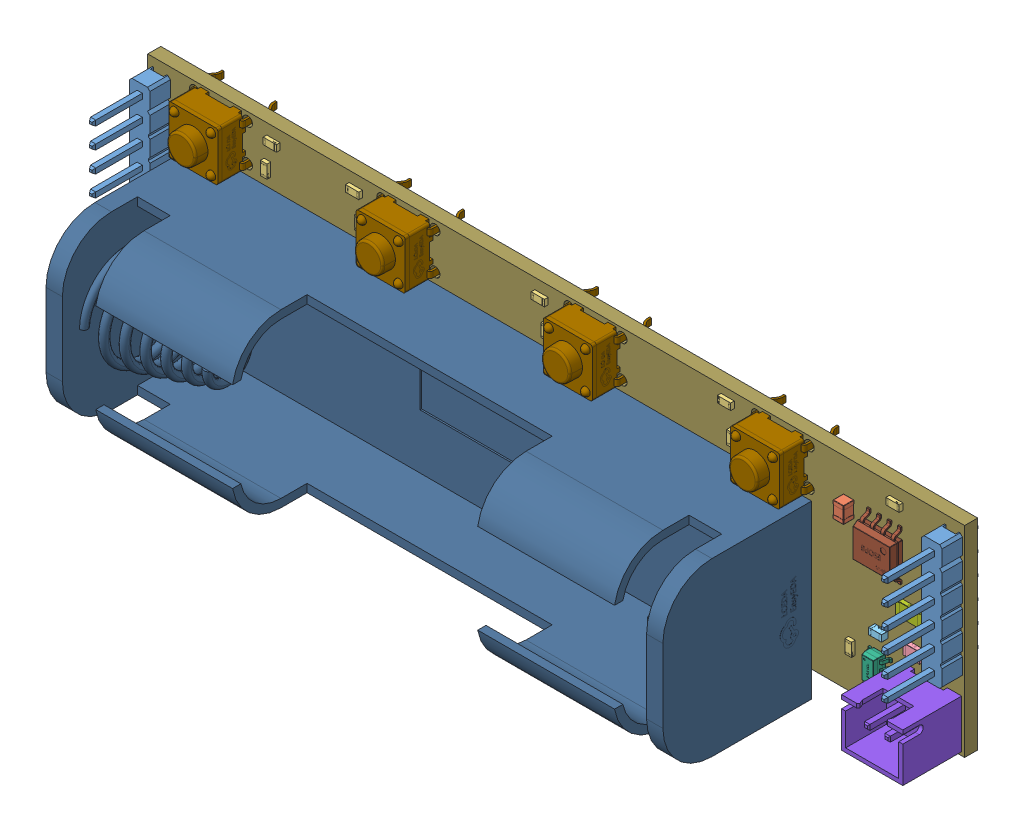
SolidWorks assembly 3D_PCB_PCB_18650_POWER_CHARGE_2024-03-23_2024-03-23, configuration 默认. Lengths in mm.
Overall size (99.98 27.76 23.2).
77 component instances, 12 part files, 0 mates.
Components (placement in the parent):
- 3D_PCB_PCB_18650_POWER_CHARGE_2024-03-23_2024-03-23.step-1: 3D_PCB_PCB_18650_POWER_CHARGE_2024-03-23_2024-03-23.step [默认] at origin size (99.98 27.76 23.2)
  - H1.step-1: H1.step [默认] at (2.8372 42.3622 1.6) x (0 1 0) z (0 0 1) size (15.25 2.5 11.5)
    - footprint_f8ae.step-1: footprint_f8ae.step [默认] at origin size (15.25 2.5 11.5)
      - SOLID.step-1: SOLID.step [默认] at origin size (15.25 2.5 11.5)
  - H2.step-1: H2.step [默认] at (99.7866 42.3546 1.6) x (0 1 0) z (0 0 1) size (15.25 2.5 11.5)
    - footprint_f8ae.step-1: footprint_f8ae.step [默认] at origin size (15.25 2.5 11.5)
      - SOLID.step-1: SOLID.step [默认] at origin size (15.25 2.5 11.5)
  - C1.step-1: C1.step [默认] at (87.1222 45.9919 1.6) x (0 1 0) z (0 0 1) size (2 1.3 1.3)
    - footprint_bf19.step-1: footprint_bf19.step [默认] at origin size (2 1.3 1.3)
      - SOLID-0.step-1: SOLID-0.step [默认] at origin size (2 1.3 1.3)
  - R2.step-1: R2.step [默认] at (16.7082 49.3294 1.6) x (-1 0 0) z (0 0 1) size (1.62 0.81 0.45)
    - footprint_4858.step-1: footprint_4858.step [默认] at origin size (1.62 0.81 0.45)
      - COMPOUND.step-1: COMPOUND.step [默认] at origin size (1.62 0.81 0.45)
  - R7.step-1: R7.step [默认] at (49.5098 49.3294 1.6) size (1.62 0.81 0.45)
    - footprint_4858.step-1: footprint_4858.step [默认] at origin size (1.62 0.81 0.45)
      - COMPOUND.step-1: COMPOUND.step [默认] at origin size (1.62 0.81 0.45)
  - R6.step-1: R6.step [默认] at (73.0251 46.2891 1.6) x (0 1 0) z (0 0 1) size (1.62 0.81 0.45)
    - footprint_4858.step-1: footprint_4858.step [默认] at origin size (1.62 0.81 0.45)
      - COMPOUND.step-1: COMPOUND.step [默认] at origin size (1.62 0.81 0.45)
  - R8.step-1: R8.step [默认] at (50.3226 46.2891 1.6) x (0 1 0) z (0 0 1) size (1.62 0.81 0.45)
    - footprint_4858.step-1: footprint_4858.step [默认] at origin size (1.62 0.81 0.45)
      - COMPOUND.step-1: COMPOUND.step [默认] at origin size (1.62 0.81 0.45)
  - R9.step-1: R9.step [默认] at (27.5083 46.2891 1.6) x (0 1 0) z (0 0 1) size (1.62 0.81 0.45)
    - footprint_4858.step-1: footprint_4858.step [默认] at origin size (1.62 0.81 0.45)
      - COMPOUND.step-1: COMPOUND.step [默认] at origin size (1.62 0.81 0.45)
  - R10.step-1: R10.step [默认] at (15.969 46.2891 1.6) x (0 1 0) z (0 0 1) size (1.62 0.81 0.45)
    - footprint_4858.step-1: footprint_4858.step [默认] at origin size (1.62 0.81 0.45)
      - COMPOUND.step-1: COMPOUND.step [默认] at origin size (1.62 0.81 0.45)
  - R3.step-1: R3.step [默认] at (92.9286 49.2583 1.6) x (-1 0 0) z (0 0 1) size (1.62 0.81 0.45)
    - footprint_4858.step-1: footprint_4858.step [默认] at origin size (1.62 0.81 0.45)
      - COMPOUND.step-1: COMPOUND.step [默认] at origin size (1.62 0.81 0.45)
  - R5.step-1: R5.step [默认] at (72.2962 49.7358 1.6) size (1.62 0.81 0.45)
    - footprint_4858.step-1: footprint_4858.step [默认] at origin size (1.62 0.81 0.45)
      - COMPOUND.step-1: COMPOUND.step [默认] at origin size (1.62 0.81 0.45)
  - R26.step-1: R26.step [默认] at (87.5032 31.3691 1.6) x (0 1 0) z (0 0 1) size (1.62 0.81 0.45)
    - footprint_4858.step-1: footprint_4858.step [默认] at origin size (1.62 0.81 0.45)
      - COMPOUND.step-1: COMPOUND.step [默认] at origin size (1.62 0.81 0.45)
  - R1.step-1: R1.step [默认] at (26.7894 49.3294 1.6) size (1.62 0.81 0.45)
    - footprint_4858.step-1: footprint_4858.step [默认] at origin size (1.62 0.81 0.45)
      - COMPOUND.step-1: COMPOUND.step [默认] at origin size (1.62 0.81 0.45)
  - R25.step-1: R25.step [默认] at (95.3772 34.7981 1.6) size (2 1.3 0.61)
    - footprint_7ba0.step-1: footprint_7ba0.step [默认] at origin size (2 1.3 0.61)
      - COMPOUND-1.step-1: COMPOUND-1.step [默认] at origin size (2 1.3 0.61)
  - C37.step-1: C37.step [默认] at (91.1227 34.76 1.6) size (1.6 0.8 0.8)
    - footprint_33f1.step-1: footprint_33f1.step [默认] at origin size (1.6 0.8 0.8)
      - SOLID-2.step-1: SOLID-2.step [默认] at origin size (1.6 0.8 0.8)
  - C36.step-1: C36.step [默认] at (90.4496 28.7021 1.6) x (-1 0 0) z (0 0 1) size (1.6 0.8 0.8)
    - footprint_33f1.step-1: footprint_33f1.step [默认] at origin size (1.6 0.8 0.8)
      - SOLID-2.step-1: SOLID-2.step [默认] at origin size (1.6 0.8 0.8)
  - U12.step-1: U12.step [默认] at (91.0592 31.3691 1.6) x (-1 0 0) z (0 0 1) size (2.81 2.9 1.65)
    - footprint_4915.step-1: footprint_4915.step [默认] at origin size (2.81 2.9 1.65)
      - COMPOUND-3.step-1: COMPOUND-3.step [默认] at origin size (2.81 2.9 1.65)
  - R4.step-1: R4.step [默认] at (94.9962 38.6817 1.6) size (3.2 1.6 0.56)
    - footprint_4e6b.step-1: footprint_4e6b.step [默认] at origin size (3.2 1.6 0.56)
      - COMPOUND-4.step-1: COMPOUND-4.step [默认] at origin size (3.2 1.6 0.56)
  - CN2.step-1: CN2.step [默认] at (97.2822 30.4801 1.6) size (7.5 5.9 10.6)
    - footprint_8315.step-1: footprint_8315.step [默认] at origin size (7.5 5.9 10.6)
      - COMPOUND-5.step-1: COMPOUND-5.step [默认] at origin size (7.5 5.9 10.6)
  - SW3.step-1: SW3.step [默认] at (56.1265 47.7496 1.6) x (-1 0 0) z (0 0 1) size (8.21 6 8.4)
    - footprint_ad6a.step-1: footprint_ad6a.step [默认] at origin size (8.21 6 8.4)
      - COMPOUND-6.step-1: COMPOUND-6.step [默认] at origin size (8.21 6 8.4)
  - SW2.step-1: SW2.step [默认] at (33.2334 47.7496 1.6) x (-1 0 0) z (0 0 1) size (8.21 6 8.4)
    - footprint_ad6a.step-1: footprint_ad6a.step [默认] at origin size (8.21 6 8.4)
      - COMPOUND-6.step-1: COMPOUND-6.step [默认] at origin size (8.21 6 8.4)
  - SW4.step-1: SW4.step [默认] at (79.045 47.7496 1.6) x (-1 0 0) z (0 0 1) size (8.21 6 8.4)
    - footprint_ad6a.step-1: footprint_ad6a.step [默认] at origin size (8.21 6 8.4)
      - COMPOUND-6.step-1: COMPOUND-6.step [默认] at origin size (8.21 6 8.4)
  - SW1.step-1: SW1.step [默认] at (10.2921 47.7496 1.6) x (-1 0 0) z (0 0 1) size (8.21 6 8.4)
    - footprint_ad6a.step-1: footprint_ad6a.step [默认] at origin size (8.21 6 8.4)
      - COMPOUND-6.step-1: COMPOUND-6.step [默认] at origin size (8.21 6 8.4)
  - 18650.step-1: 18650.step [默认] at (44.8235 33.7668 1.6) size (75.51 21 23.2)
    - footprint_8e79.step-1: footprint_8e79.step [默认] at origin size (75.51 21 23.2)
      - SOLID-7.step-1: SOLID-7.step [默认] at origin size (75.51 21 23.2)
  - U6.step-1: U6.step [默认] at (91.5672 44.0691 1.6) x (-1 0 0) z (0 0 1) size (4.9 6.1 1.7)
    - footprint_f7fe.step-1: footprint_f7fe.step [默认] at origin size (4.9 6.1 1.7)
      - COMPOUND-8.step-1: COMPOUND-8.step [默认] at origin size (4.9 6.1 1.7)
  - COMPOUND-9.step-1: COMPOUND-9.step [默认] at origin size (99.98 24.59 1.6)
